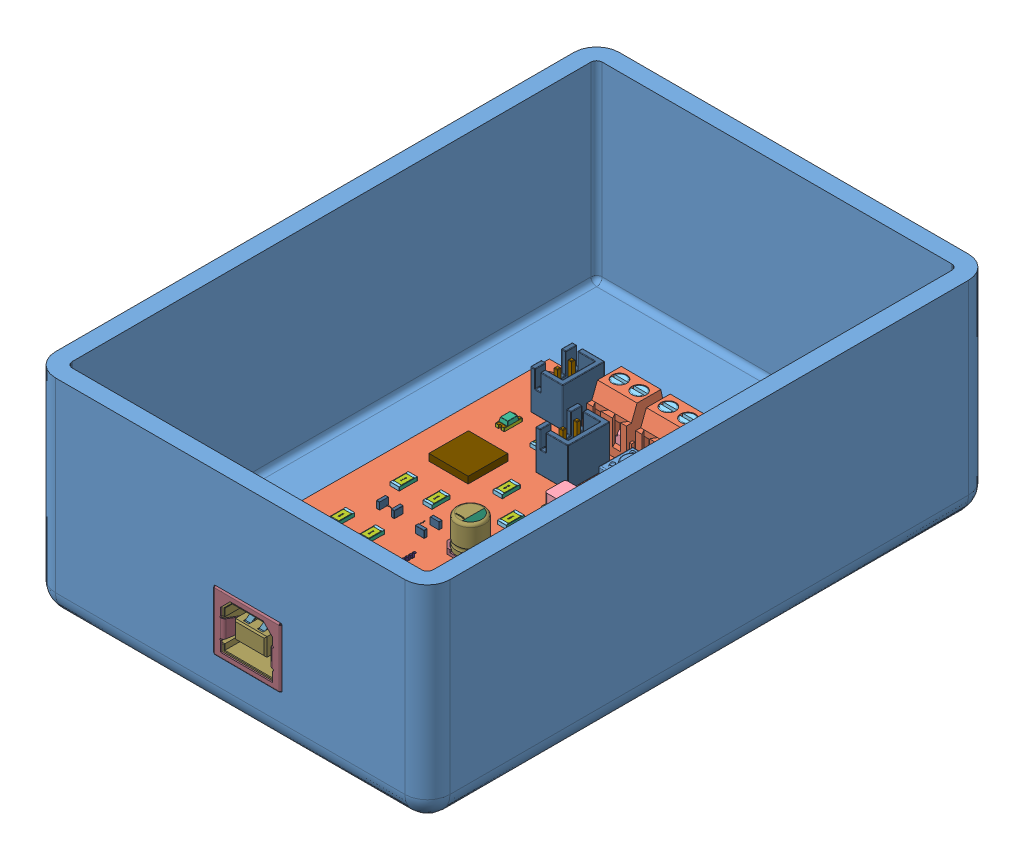
SolidWorks assembly Assembly_Main, configuration Default. Lengths in mm.
Overall size (70 37 100.3).
216 component instances, 35 part files, 2 mates.
Components (placement in the parent):
- Main_Controller_Bottom-1: Main_Controller_Bottom [Default] at (31.4196 27.2913 84.2201) size (70 37 100)
- PCB-MCU-2.step-1: PCB-MCU-2.step [Default] at (75.3064 35.4488 154.7162) x (0.004519 0 -0.99999) z (0 1 0) size (75.68 37.85 14.81)
  - Board.step-1: Board.step [Default] at origin size (70.36 37.85 0.41)
    - Open CASCADE STEP translator 7.5 3.1.1.step-1: Open CASCADE STEP translator 7.5 3.1.1.step [Default] at (0 0 -0.4115) size (70.36 37.85 0.41)
  - Y1.step-1: Y1.step [Default] at origin size (4.65 11.36 3.61)
    - 6242356320.step-1: 6242356320.step [Default] at (73.2791 34.5439 0) size (4.65 11.36 1.01)
      - Extruded.step-1: Extruded.step [Default] at origin size (4.65 11.36 1.01)
    - 6242356400.step-1: 6242356400.step [Default] at (73.2789 34.5439 1) size (3.7 10.05 2.6)
      - Extruded-0.step-1: Extruded-0.step [Default] at origin size (3.7 10.05 2.6)
  - R10.step-1: R10.step [Default] at origin size (3.2 1.6 0.65)
    - Res_Rohm_MCR18ERTFL1R10_eec.step-1: Res_Rohm_MCR18ERTFL1R10_eec.step [Default] at (39.8822 54.356 0) size (3.2 1.6 0.65)
    - Res_Rohm_MCR18ERTFL1R10_eec-1.step-1: Res_Rohm_MCR18ERTFL1R10_eec-1.step [Default] at (39.8822 54.356 0) size (3.15 1.6 0.6)
    - Res_Rohm_MCR18ERTFL1R10_eec-2.step-1: Res_Rohm_MCR18ERTFL1R10_eec-2.step [Default] at (39.8822 54.356 0) size (2.2 1.38 0.02)
    - Res_Rohm_MCR18ERTFL1R10_eec-3.step-1: Res_Rohm_MCR18ERTFL1R10_eec-3.step [Default] at (39.8822 54.356 0) size (0.94 0.2 0.01)
  - J6.step-1: J6.step [Default] at origin size (7.4 5.75 10.4)
    - Conn_JST_B2B-XH-A_LF_SN_eec.step-1: Conn_JST_B2B-XH-A_LF_SN_eec.step [Default] at (30.734 54.61 0) size (7.4 5.75 10.4)
      - 1.step-1: 1.step [Default] at (0 0.025 0) x (-1 0 0) z (0 1 0) size (7.4 10.4 5.75)
        - 1-4.step-1: 1-4.step [Default] at origin size (3.14 10.2 0.64)
        - B2B-XH-A.step-1: B2B-XH-A.step [Default] at origin size (7.4 7 5.75)
        - JST Logo adjustable.step-1: JST Logo adjustable.step [Default] at (-1.7267 5.5034 2.841) size (0.85 2.3 0.01)
  - J5.step-1: J5.step [Default] at origin size (17.39 16.2 11.97)
    - 62910416121.step-1: 62910416121.step [Default] at (28.2429 40.8111 5.85) x (0 -1 0) z (0 0 1) size (16.2 17.39 11.97)
      - 62910416121_Insulator_v2.step-1: 62910416121_Insulator_v2.step [Default] at origin size (11.54 15.82 11.72)
      - 62910416121_Shielding_v2.step-1: 62910416121_Shielding_v2.step [Default] at (0 -1.76 0) x (-1 0 0) z (0 1 0) size (16.2 11.15 16)
      - 62910416121_Pin_TOP.step-1: 62910416121_Pin_TOP.step [Default] at (-1.25 -7.258 1.225) x (0 1 0) z (0 0 1) size (16.49 2.05 8.16)
      - 62910416121_Pin_Bottom.step-1: 62910416121_Pin_Bottom.step [Default] at (-1.25 -7.258 -1.525) x (0 1 0) z (0 0 -1) size (16.47 1.78 5.44)
      - 62910416121_Pin_TOP.step-2: 62910416121_Pin_TOP.step [Default] at (1.245 -7.258 1.225) x (0 1 0) z (0 0 1) size (16.49 2.05 8.16)
      - 62910416121_Pin_Bottom.step-2: 62910416121_Pin_Bottom.step [Default] at (1.25 -7.258 -1.525) x (0 1 0) z (0 0 -1) size (16.47 1.78 5.44)
  - U2.step-1: U2.step [Default] at origin size (14.3 7.8 1.91)
    - 8026914064.step-1: 8026914064.step [Default] at (48.895 41.275 0) x (0 1 0) z (0 0 1) size (7.8 14.3 1.91)
      - Body.step-1: Body.step [Default] at (-2.8 -5.25 0)
        - Open CASCADE STEP translator 6.8 6.2.1.x_t-1: Open CASCADE STEP translator 6.8 6.2.1.x_t [Default] at origin
      - Open CASCADE STEP translator 6.8 6.1.step-1: Open CASCADE STEP translator 6.8 6.1.step [Default] at (-2.8 -5.25 0.001) size (0.71 0.71 0.01)
      - Leader.step-1: Leader.step [Default] at (-2.8 -4.225 0) x (-1 0 0) z (0 0 1) size (1.1 0.3 1.07)
      - Leader.step-2: Leader.step [Default] at (-2.8 -3.575 0) x (-1 0 0) z (0 0 1) size (1.1 0.3 1.07)
      - Leader.step-3: Leader.step [Default] at (-2.8 -2.925 0) x (-1 0 0) z (0 0 1) size (1.1 0.3 1.07)
      - Leader.step-4: Leader.step [Default] at (-2.8 -2.275 0) x (-1 0 0) z (0 0 1) size (1.1 0.3 1.07)
      - Leader.step-5: Leader.step [Default] at (-2.8 -1.625 0) x (-1 0 0) z (0 0 1) size (1.1 0.3 1.07)
      - Leader.step-6: Leader.step [Default] at (-2.8 -0.975 0) x (-1 0 0) z (0 0 1) size (1.1 0.3 1.07)
      - Leader.step-7: Leader.step [Default] at (-2.8 -0.325 0) x (-1 0 0) z (0 0 1) size (1.1 0.3 1.07)
      - Leader.step-8: Leader.step [Default] at (-2.8 0.325 0) x (-1 0 0) z (0 0 1) size (1.1 0.3 1.07)
      - Leader.step-9: Leader.step [Default] at (-2.8 0.975 0) x (-1 0 0) z (0 0 1) size (1.1 0.3 1.07)
      - Leader.step-10: Leader.step [Default] at (-2.8 1.625 0) x (-1 0 0) z (0 0 1) size (1.1 0.3 1.07)
      - Leader.step-11: Leader.step [Default] at (-2.8 2.275 0) x (-1 0 0) z (0 0 1) size (1.1 0.3 1.07)
      - Leader.step-12: Leader.step [Default] at (-2.8 2.925 0) x (-1 0 0) z (0 0 1) size (1.1 0.3 1.07)
      - Leader.step-13: Leader.step [Default] at (-2.8 3.575 0) x (-1 0 0) z (0 0 1) size (1.1 0.3 1.07)
      - Leader.step-14: Leader.step [Default] at (-2.8 4.225 0) x (-1 0 0) z (0 0 1) size (1.1 0.3 1.07)
      - Leader.step-15: Leader.step [Default] at (2.8 -4.225 0) size (1.1 0.3 1.07)
      - Leader.step-16: Leader.step [Default] at (2.8 -3.575 0) size (1.1 0.3 1.07)
      - Leader.step-17: Leader.step [Default] at (2.8 -2.925 0) size (1.1 0.3 1.07)
      - Leader.step-18: Leader.step [Default] at (2.8 -2.275 0) size (1.1 0.3 1.07)
      - Leader.step-19: Leader.step [Default] at (2.8 -1.625 0) size (1.1 0.3 1.07)
      - Leader.step-20: Leader.step [Default] at (2.8 -0.975 0) size (1.1 0.3 1.07)
      - Leader.step-21: Leader.step [Default] at (2.8 -0.325 0) size (1.1 0.3 1.07)
      - Leader.step-22: Leader.step [Default] at (2.8 0.325 0) size (1.1 0.3 1.07)
      - Leader.step-23: Leader.step [Default] at (2.8 0.975 0) size (1.1 0.3 1.07)
      - Leader.step-24: Leader.step [Default] at (2.8 1.625 0) size (1.1 0.3 1.07)
      - Leader.step-25: Leader.step [Default] at (2.8 2.275 0) size (1.1 0.3 1.07)
      - Leader.step-26: Leader.step [Default] at (2.8 2.925 0) size (1.1 0.3 1.07)
      - Leader.step-27: Leader.step [Default] at (2.8 3.575 0) size (1.1 0.3 1.07)
      - Leader.step-28: Leader.step [Default] at (2.8 4.225 0) size (1.1 0.3 1.07)
  - U1.step-1: U1.step [Default] at origin size (7 7 1.2)
    - 7799090928.step-1: 7799090928.step [Default] at (72.898 54.61 0) size (7 7 1.2)
      - Extruded-5.step-1: Extruded-5.step [Default] at origin size (7 7 1.2)
  - SW1.step-1: SW1.step [Default] at origin size (6 7.9 7.79)
    - Switch_C&K_PTS645SM43SMTR92LFS_eec.step-1: Switch_C&K_PTS645SM43SMTR92LFS_eec.step [Default] at (79.883 32.385 0) x (0 1 0) z (0 0 1) size (7.9 6 7.79)
  - R9.step-1: R9.step [Default] at origin size (1.6 3.2 0.65)
    - Res_Rohm_MCR18ERTFL1R10_eec.step-1: Res_Rohm_MCR18ERTFL1R10_eec.step [Default] at (40.386 44.323 0) x (0 1 0) z (0 0 1) size (3.2 1.6 0.65)
    - Res_Rohm_MCR18ERTFL1R10_eec-1.step-1: Res_Rohm_MCR18ERTFL1R10_eec-1.step [Default] at (40.386 44.323 0) x (0 1 0) z (0 0 1) size (3.15 1.6 0.6)
    - Res_Rohm_MCR18ERTFL1R10_eec-2.step-1: Res_Rohm_MCR18ERTFL1R10_eec-2.step [Default] at (40.386 44.323 0) x (0 1 0) z (0 0 1) size (2.2 1.38 0.02)
    - Res_Rohm_MCR18ERTFL1R10_eec-3.step-1: Res_Rohm_MCR18ERTFL1R10_eec-3.step [Default] at (40.386 44.323 0) x (0 1 0) z (0 0 1) size (0.94 0.2 0.01)
  - R8.step-1: R8.step [Default] at origin size (3.2 1.6 0.65)
    - Res_Rohm_MCR18ERTFL1R10_eec.step-1: Res_Rohm_MCR18ERTFL1R10_eec.step [Default] at (52.705 51.562 0) x (1 0 0) z (0 0 1) size (3.2 1.6 0.65)
    - Res_Rohm_MCR18ERTFL1R10_eec-1.step-1: Res_Rohm_MCR18ERTFL1R10_eec-1.step [Default] at (52.705 51.562 0) x (1 0 0) z (0 0 1) size (3.15 1.6 0.6)
    - Res_Rohm_MCR18ERTFL1R10_eec-2.step-1: Res_Rohm_MCR18ERTFL1R10_eec-2.step [Default] at (52.705 51.562 0) x (1 0 0) z (0 0 1) size (2.2 1.38 0.02)
    - Res_Rohm_MCR18ERTFL1R10_eec-3.step-1: Res_Rohm_MCR18ERTFL1R10_eec-3.step [Default] at (52.705 51.562 0) x (1 0 0) z (0 0 1) size (0.94 0.2 0.01)
  - R7.step-1: R7.step [Default] at origin size (3.2 1.6 0.65)
    - Res_Rohm_MCR18ERTFL1R10_eec.step-1: Res_Rohm_MCR18ERTFL1R10_eec.step [Default] at (52.705 56.896 0) x (1 0 0) z (0 0 1) size (3.2 1.6 0.65)
    - Res_Rohm_MCR18ERTFL1R10_eec-1.step-1: Res_Rohm_MCR18ERTFL1R10_eec-1.step [Default] at (52.705 56.896 0) x (1 0 0) z (0 0 1) size (3.15 1.6 0.6)
    - Res_Rohm_MCR18ERTFL1R10_eec-2.step-1: Res_Rohm_MCR18ERTFL1R10_eec-2.step [Default] at (52.705 56.896 0) x (1 0 0) z (0 0 1) size (2.2 1.38 0.02)
    - Res_Rohm_MCR18ERTFL1R10_eec-3.step-1: Res_Rohm_MCR18ERTFL1R10_eec-3.step [Default] at (52.705 56.896 0) x (1 0 0) z (0 0 1) size (0.94 0.2 0.01)
  - R6.step-1: R6.step [Default] at origin size (3.2 1.6 0.65)
    - Res_Rohm_MCR18ERTFL1R10_eec.step-1: Res_Rohm_MCR18ERTFL1R10_eec.step [Default] at (63.754 56.896 0) size (3.2 1.6 0.65)
    - Res_Rohm_MCR18ERTFL1R10_eec-1.step-1: Res_Rohm_MCR18ERTFL1R10_eec-1.step [Default] at (63.754 56.896 0) size (3.15 1.6 0.6)
    - Res_Rohm_MCR18ERTFL1R10_eec-2.step-1: Res_Rohm_MCR18ERTFL1R10_eec-2.step [Default] at (63.754 56.896 0) size (2.2 1.38 0.02)
    - Res_Rohm_MCR18ERTFL1R10_eec-3.step-1: Res_Rohm_MCR18ERTFL1R10_eec-3.step [Default] at (63.754 56.896 0) size (0.94 0.2 0.01)
  - R5.step-1: R5.step [Default] at origin size (3.2 1.6 0.65)
    - Res_Rohm_MCR18ERTFL1R10_eec.step-1: Res_Rohm_MCR18ERTFL1R10_eec.step [Default] at (63.881 51.181 0) size (3.2 1.6 0.65)
    - Res_Rohm_MCR18ERTFL1R10_eec-1.step-1: Res_Rohm_MCR18ERTFL1R10_eec-1.step [Default] at (63.881 51.181 0) size (3.15 1.6 0.6)
    - Res_Rohm_MCR18ERTFL1R10_eec-2.step-1: Res_Rohm_MCR18ERTFL1R10_eec-2.step [Default] at (63.881 51.181 0) size (2.2 1.38 0.02)
    - Res_Rohm_MCR18ERTFL1R10_eec-3.step-1: Res_Rohm_MCR18ERTFL1R10_eec-3.step [Default] at (63.881 51.181 0) size (0.94 0.2 0.01)
  - R4.step-1: R4.step [Default] at origin size (3.2 1.6 0.65)
    - Res_Rohm_MCR18ERTFL1R10_eec.step-1: Res_Rohm_MCR18ERTFL1R10_eec.step [Default] at (82.169 50.546 0) size (3.2 1.6 0.65)
    - Res_Rohm_MCR18ERTFL1R10_eec-1.step-1: Res_Rohm_MCR18ERTFL1R10_eec-1.step [Default] at (82.169 50.546 0) size (3.15 1.6 0.6)
    - Res_Rohm_MCR18ERTFL1R10_eec-2.step-1: Res_Rohm_MCR18ERTFL1R10_eec-2.step [Default] at (82.169 50.546 0) size (2.2 1.38 0.02)
    - Res_Rohm_MCR18ERTFL1R10_eec-3.step-1: Res_Rohm_MCR18ERTFL1R10_eec-3.step [Default] at (82.169 50.546 0) size (0.94 0.2 0.01)
  - R3.step-1: R3.step [Default] at origin size (3.2 1.6 0.65)
    - Res_Rohm_MCR18ERTFL1R10_eec.step-1: Res_Rohm_MCR18ERTFL1R10_eec.step [Default] at (67.4412 41.529 0) x (1 0 0) z (0 0 1) size (3.2 1.6 0.65)
    - Res_Rohm_MCR18ERTFL1R10_eec-1.step-1: Res_Rohm_MCR18ERTFL1R10_eec-1.step [Default] at (67.4412 41.529 0) x (1 0 0) z (0 0 1) size (3.15 1.6 0.6)
    - Res_Rohm_MCR18ERTFL1R10_eec-2.step-1: Res_Rohm_MCR18ERTFL1R10_eec-2.step [Default] at (67.4412 41.529 0) x (1 0 0) z (0 0 1) size (2.2 1.38 0.02)
    - Res_Rohm_MCR18ERTFL1R10_eec-3.step-1: Res_Rohm_MCR18ERTFL1R10_eec-3.step [Default] at (67.4412 41.529 0) x (1 0 0) z (0 0 1) size (0.94 0.2 0.01)
  - R2.step-1: R2.step [Default] at origin size (3.2 1.6 0.65)
    - Res_Rohm_MCR18ERTFL1R10_eec.step-1: Res_Rohm_MCR18ERTFL1R10_eec.step [Default] at (71.755 46.609 0) x (1 0 0) z (0 0 1) size (3.2 1.6 0.65)
    - Res_Rohm_MCR18ERTFL1R10_eec-1.step-1: Res_Rohm_MCR18ERTFL1R10_eec-1.step [Default] at (71.755 46.609 0) x (1 0 0) z (0 0 1) size (3.15 1.6 0.6)
    - Res_Rohm_MCR18ERTFL1R10_eec-2.step-1: Res_Rohm_MCR18ERTFL1R10_eec-2.step [Default] at (71.755 46.609 0) x (1 0 0) z (0 0 1) size (2.2 1.38 0.02)
    - Res_Rohm_MCR18ERTFL1R10_eec-3.step-1: Res_Rohm_MCR18ERTFL1R10_eec-3.step [Default] at (71.755 46.609 0) x (1 0 0) z (0 0 1) size (0.94 0.2 0.01)
  - R1.step-1: R1.step [Default] at origin size (3.2 1.6 0.65)
    - Res_Rohm_MCR18ERTFL1R10_eec.step-1: Res_Rohm_MCR18ERTFL1R10_eec.step [Default] at (67.564 35.814 0) x (1 0 0) z (0 0 1) size (3.2 1.6 0.65)
    - Res_Rohm_MCR18ERTFL1R10_eec-1.step-1: Res_Rohm_MCR18ERTFL1R10_eec-1.step [Default] at (67.564 35.814 0) x (1 0 0) z (0 0 1) size (3.15 1.6 0.6)
    - Res_Rohm_MCR18ERTFL1R10_eec-2.step-1: Res_Rohm_MCR18ERTFL1R10_eec-2.step [Default] at (67.564 35.814 0) x (1 0 0) z (0 0 1) size (2.2 1.38 0.02)
    - Res_Rohm_MCR18ERTFL1R10_eec-3.step-1: Res_Rohm_MCR18ERTFL1R10_eec-3.step [Default] at (67.564 35.814 0) x (1 0 0) z (0 0 1) size (0.94 0.2 0.01)
  - J4.step-1: J4.step [Default] at origin size (7.4 5.75 10.4)
    - Conn_JST_B2B-XH-A_LF_SN_eec.step-1: Conn_JST_B2B-XH-A_LF_SN_eec.step [Default] at (80.899 44.069 0) size (7.4 5.75 10.4)
      - 1.step-1: 1.step [Default] at (0 0.025 0) x (-1 0 0) z (0 1 0) size (7.4 10.4 5.75)
        - 1-4.step-1: 1-4.step [Default] at origin size (3.14 10.2 0.64)
        - B2B-XH-A.step-1: B2B-XH-A.step [Default] at origin size (7.4 7 5.75)
        - JST Logo adjustable.step-1: JST Logo adjustable.step [Default] at (-1.7267 5.5034 2.841) size (0.85 2.3 0.01)
  - J3.step-1: J3.step [Default] at origin size (7.4 5.75 10.4)
    - Conn_JST_B2B-XH-A_LF_SN_eec.step-1: Conn_JST_B2B-XH-A_LF_SN_eec.step [Default] at (89.662 53.848 0) size (7.4 5.75 10.4)
      - 1.step-1: 1.step [Default] at (0 0.025 0) x (-1 0 0) z (0 1 0) size (7.4 10.4 5.75)
        - 1-4.step-1: 1-4.step [Default] at origin size (3.14 10.2 0.64)
        - B2B-XH-A.step-1: B2B-XH-A.step [Default] at origin size (7.4 7 5.75)
        - JST Logo adjustable.step-1: JST Logo adjustable.step [Default] at (-1.7267 5.5034 2.841) size (0.85 2.3 0.01)
  - J2.step-1: J2.step [Default] at origin size (7.4 7.45 12.2)
    - 691214110002.step-1: 691214110002.step [Default] at (90.251 35.0549 3) x (0 1 0) z (0 0 1) size (7.45 7.4 12.2)
      - 691214110002-6.step-1: 691214110002-6.step [Default] at origin size (7.45 7.4 8.5)
      - 6912141100xx_CAGE.step-1: 6912141100xx_CAGE.step [Default] at (1.725 -0.3 -0.125) size (2.6 3.95 4.15)
      - 6912141100xx_CAGE.step-2: 6912141100xx_CAGE.step [Default] at (-1.775 -0.3 -0.125) size (2.6 3.95 4.15)
      - 6912141100xx_PIN.step-1: 6912141100xx_PIN.step [Default] at (1.775 0.145 -1.2) x (1 0 0) z (0 1 0) size (2 7.15 4.8)
      - 6912141100xx_PIN.step-2: 6912141100xx_PIN.step [Default] at (-1.725 0.145 -1.2) x (1 0 0) z (0 1 0) size (2 7.15 4.8)
      - 6912141100xx_VIS.step-1: 6912141100xx_VIS.step [Default] at (1.725 -0.3 4.45) size (2.6 2.6 4.2)
      - 6912141100xx_VIS.step-2: 6912141100xx_VIS.step [Default] at (-1.775 -0.3 4.45) size (2.6 2.6 4.2)
  - J1.step-1: J1.step [Default] at origin size (7.4 7.45 12.2)
    - 691214110002.step-1: 691214110002.step [Default] at (90.124 43.6349 3) x (0 1 0) z (0 0 1) size (7.45 7.4 12.2)
      - 691214110002-6.step-1: 691214110002-6.step [Default] at origin size (7.45 7.4 8.5)
      - 6912141100xx_CAGE.step-1: 6912141100xx_CAGE.step [Default] at (1.725 -0.3 -0.125) size (2.6 3.95 4.15)
      - 6912141100xx_CAGE.step-2: 6912141100xx_CAGE.step [Default] at (-1.775 -0.3 -0.125) size (2.6 3.95 4.15)
      - 6912141100xx_PIN.step-1: 6912141100xx_PIN.step [Default] at (1.775 0.145 -1.2) x (1 0 0) z (0 1 0) size (2 7.15 4.8)
      - 6912141100xx_PIN.step-2: 6912141100xx_PIN.step [Default] at (-1.725 0.145 -1.2) x (1 0 0) z (0 1 0) size (2 7.15 4.8)
      - 6912141100xx_VIS.step-1: 6912141100xx_VIS.step [Default] at (1.725 -0.3 4.45) size (2.6 2.6 4.2)
      - 6912141100xx_VIS.step-2: 6912141100xx_VIS.step [Default] at (-1.775 -0.3 4.45) size (2.6 2.6 4.2)
  - D4.step-1: D4.step [Default] at origin size (1.6 3.2 1.2)
    - Diode_Broadcom_HSMG-C150_eec.step-1: Diode_Broadcom_HSMG-C150_eec.step [Default] at (40.386 35.052 0) x (0 1 0) z (0 0 1) size (3.2 1.6 1.2)
      - 1-7.step-1: 1-7.step [Default] at origin size (2 1.6 0.66)
      - 2.step-1: 2.step [Default] at origin size (3.2 1.6 0.53)
      - 3.step-1: 3.step [Default] at origin size (0.35 1.6 0.01)
      - 4.step-1: 4.step [Default] at origin size (3.2 1.3 0.55)
  - D3.step-1: D3.step [Default] at origin size (3.2 1.6 1.2)
    - Diode_Broadcom_HSMG-C150_eec.step-1: Diode_Broadcom_HSMG-C150_eec.step [Default] at (46.609 51.562 0) x (1 0 0) z (0 0 1) size (3.2 1.6 1.2)
      - 1-7.step-1: 1-7.step [Default] at origin size (2 1.6 0.66)
      - 2.step-1: 2.step [Default] at origin size (3.2 1.6 0.53)
      - 3.step-1: 3.step [Default] at origin size (0.35 1.6 0.01)
      - 4.step-1: 4.step [Default] at origin size (3.2 1.3 0.55)
  - D2.step-1: D2.step [Default] at origin size (3.2 1.6 1.2)
    - Diode_Broadcom_HSMG-C150_eec.step-1: Diode_Broadcom_HSMG-C150_eec.step [Default] at (46.609 56.896 0) x (1 0 0) z (0 0 1) size (3.2 1.6 1.2)
      - 1-7.step-1: 1-7.step [Default] at origin size (2 1.6 0.66)
      - 2.step-1: 2.step [Default] at origin size (3.2 1.6 0.53)
      - 3.step-1: 3.step [Default] at origin size (0.35 1.6 0.01)
      - 4.step-1: 4.step [Default] at origin size (3.2 1.3 0.55)
  - D1.step-1: D1.step [Default] at origin size (3.2 1.6 1.2)
    - Diode_Broadcom_HSMG-C150_eec.step-1: Diode_Broadcom_HSMG-C150_eec.step [Default] at (82.197 56.769 0) x (-1 0 0) z (0 0 1) size (3.2 1.6 1.2)
      - 1-7.step-1: 1-7.step [Default] at origin size (2 1.6 0.66)
      - 2.step-1: 2.step [Default] at origin size (3.2 1.6 0.53)
      - 3.step-1: 3.step [Default] at origin size (0.35 1.6 0.01)
      - 4.step-1: 4.step [Default] at origin size (3.2 1.3 0.55)
  - C7.step-1: C7.step [Default] at origin size (3.2 1.6 1.26)
    - Cap_Murata_GRM31M3U1H683JA01K_eec.step-1: Cap_Murata_GRM31M3U1H683JA01K_eec.step [Default] at (58.7218 47.371 0) x (-1 0 0) z (0 0 1) size (3.2 1.6 1.26)
      - Body.step-1: Body.step [Default] x (-1 0 0) z (0 0 1)
        - Open CASCADE STEP translator 6.8 6.2.1.x_t-1: Open CASCADE STEP translator 6.8 6.2.1.x_t [Default] at origin
      - side.step-1: side.step [Default] at (-1.3 0.0917 0) x (-1 0 0) z (0 0 1) size (0.55 1.6 1.25)
      - side.step-2: side.step [Default] at (1.3 0.0917 1.25) x (1 0 0) z (0 0 -1) size (0.55 1.6 1.25)
      - Murata.step-1: Murata.step [Default] at (-0.5 -1.0194 1.2465) size (0.91 0.21 0.01)
  - C6.step-1: C6.step [Default] at origin size (3.2 1.6 1.26)
    - Cap_Murata_GRM31M3U1H683JA01K_eec.step-1: Cap_Murata_GRM31M3U1H683JA01K_eec.step [Default] at (45.6408 29.845 0) x (1 0 0) z (0 0 1) size (3.2 1.6 1.26)
      - Body.step-1: Body.step [Default] x (-1 0 0) z (0 0 1)
        - Open CASCADE STEP translator 6.8 6.2.1.x_t-1: Open CASCADE STEP translator 6.8 6.2.1.x_t [Default] at origin
      - side.step-1: side.step [Default] at (-1.3 0.0917 0) x (-1 0 0) z (0 0 1) size (0.55 1.6 1.25)
      - side.step-2: side.step [Default] at (1.3 0.0917 1.25) x (1 0 0) z (0 0 -1) size (0.55 1.6 1.25)
      - Murata.step-1: Murata.step [Default] at (-0.5 -1.0194 1.2465) size (0.91 0.21 0.01)
  - C5.step-1: C5.step [Default] at origin size (5.3 6 5.82)
    - Cap_Panasonic_Electronic_Components_EEE-1AA101WR_eec.step-1: Cap_Panasonic_Electronic_Components_EEE-1AA101WR_eec.step [Default] at (59.436 40.64 0) x (0 1 0) z (0 0 1) size (6 5.3 5.82)
      - _____5 SIZE CODE C.step-1: _____5 SIZE CODE C.step [Default] x (1 0 0) z (0 -1 0) size (6 5.82 5.3)
        - ___W_____SIZE CODE C-001.step-1: ___W_____SIZE CODE C-001.step [Default] at (0 0.5 0) size (5 5.3 5)
        - ___W_____SIZE CODE C-002.step-1: ___W_____SIZE CODE C-002.step [Default] at origin size (5.3 1.45 5.3)
        - ___W_____SIZE CODE C-003.step-1: ___W_____SIZE CODE C-003.step [Default] at (-0.75 0.3 0) size (2.58 1 0.65)
        - ___W_____SIZE CODE C-003.step-2: ___W_____SIZE CODE C-003.step [Default] at (0.75 0.3 0) x (-1 0 0) z (0 0 -1) size (2.58 1 0.65)
        - 1-8.step-1: 1-8.step [Default] at (0 0.499 0) size (1.49 0.2 3.86)
        - Panasonic Logo.step-1: Panasonic Logo.step [Default] at (-0.9594 5.701 -1.5139) x (1 0 0) z (0 1 0) size (1.5 0.24 0.15)
  - C4.step-1: C4.step [Default] at origin size (3.2 1.6 1.26)
    - Cap_Murata_GRM31M3U1H683JA01K_eec.step-1: Cap_Murata_GRM31M3U1H683JA01K_eec.step [Default] at (67.056 30.099 0) x (-1 0 0) z (0 0 1) size (3.2 1.6 1.26)
      - Body.step-1: Body.step [Default] x (-1 0 0) z (0 0 1)
        - Open CASCADE STEP translator 6.8 6.2.1.x_t-1: Open CASCADE STEP translator 6.8 6.2.1.x_t [Default] at origin
      - side.step-1: side.step [Default] at (-1.3 0.0917 0) x (-1 0 0) z (0 0 1) size (0.55 1.6 1.25)
      - side.step-2: side.step [Default] at (1.3 0.0917 1.25) x (1 0 0) z (0 0 -1) size (0.55 1.6 1.25)
      - Murata.step-1: Murata.step [Default] at (-0.5 -1.0194 1.2465) size (0.91 0.21 0.01)
  - C3.step-1: C3.step [Default] at origin size (3.2 1.6 1.26)
    - Cap_Murata_GRM31M3U1H683JA01K_eec.step-1: Cap_Murata_GRM31M3U1H683JA01K_eec.step [Default] at (59.1028 29.972 0) x (1 0 0) z (0 0 1) size (3.2 1.6 1.26)
      - Body.step-1: Body.step [Default] x (-1 0 0) z (0 0 1)
        - Open CASCADE STEP translator 6.8 6.2.1.x_t-1: Open CASCADE STEP translator 6.8 6.2.1.x_t [Default] at origin
      - side.step-1: side.step [Default] at (-1.3 0.0917 0) x (-1 0 0) z (0 0 1) size (0.55 1.6 1.25)
      - side.step-2: side.step [Default] at (1.3 0.0917 1.25) x (1 0 0) z (0 0 -1) size (0.55 1.6 1.25)
      - Murata.step-1: Murata.step [Default] at (-0.5 -1.0194 1.2465) size (0.91 0.21 0.01)
  - C2.step-1: C2.step [Default] at origin size (1.6 3.2 1.26)
    - Cap_Murata_GRM31M3U1H683JA01K_eec.step-1: Cap_Murata_GRM31M3U1H683JA01K_eec.step [Default] at (58.293 53.848 0) x (0 -1 0) z (0 0 1) size (3.2 1.6 1.26)
      - Body.step-1: Body.step [Default] x (-1 0 0) z (0 0 1)
        - Open CASCADE STEP translator 6.8 6.2.1.x_t-1: Open CASCADE STEP translator 6.8 6.2.1.x_t [Default] at origin
      - side.step-1: side.step [Default] at (-1.3 0.0917 0) x (-1 0 0) z (0 0 1) size (0.55 1.6 1.25)
      - side.step-2: side.step [Default] at (1.3 0.0917 1.25) x (1 0 0) z (0 0 -1) size (0.55 1.6 1.25)
      - Murata.step-1: Murata.step [Default] at (-0.5 -1.0194 1.2465) size (0.91 0.21 0.01)
  - C1.step-1: C1.step [Default] at origin size (3.2 1.6 1.26)
    - Cap_Murata_GRM31M3U1H683JA01K_eec.step-1: Cap_Murata_GRM31M3U1H683JA01K_eec.step [Default] at (52.324 29.972 0) x (-1 0 0) z (0 0 1) size (3.2 1.6 1.26)
      - Body.step-1: Body.step [Default] x (-1 0 0) z (0 0 1)
        - Open CASCADE STEP translator 6.8 6.2.1.x_t-1: Open CASCADE STEP translator 6.8 6.2.1.x_t [Default] at origin
      - side.step-1: side.step [Default] at (-1.3 0.0917 0) x (-1 0 0) z (0 0 1) size (0.55 1.6 1.25)
      - side.step-2: side.step [Default] at (1.3 0.0917 1.25) x (1 0 0) z (0 0 -1) size (0.55 1.6 1.25)
      - Murata.step-1: Murata.step [Default] at (-0.5 -1.0194 1.2465) size (0.91 0.21 0.01)
Mates (geometry in assembly coordinates):
- Coincident1: coincident anti-aligned: plane of Main_Controller_Bottom-1 through (47.5658 35.0373 125.5967) normal (0 1 0); plane of PCB-MCU-2.step-1/Board.step-1/Open CASCADE STEP translator 7.5 3.1.1.step-1 through (31.2576 35.0373 93.9376) normal (0 -1 0)
- Coincident2: coincident aligned: circle of Main_Controller_Bottom-1; circle of PCB-MCU-2.step-1/Board.step-1/Open CASCADE STEP translator 7.5 3.1.1.step-1
